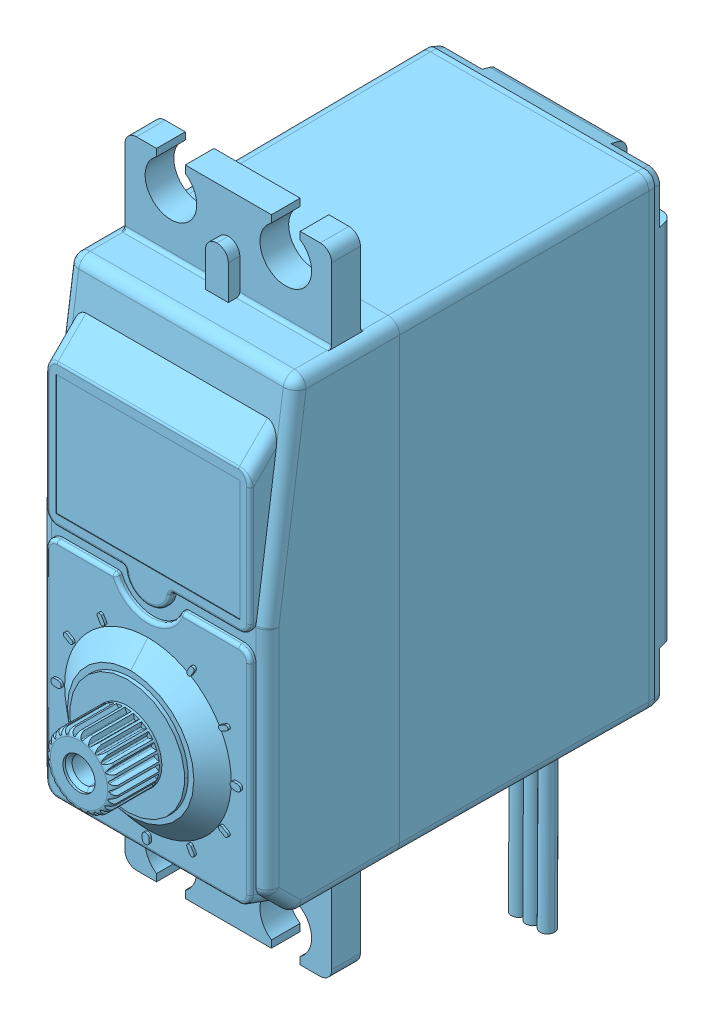
SolidWorks assembly Servo, configuration Default. Lengths in mm.
Overall size (20.01 68.31 42.11).
9 component instances, 7 part files, 0 mates.
Components (placement in the parent):
- Parallax-900-00005-08-25-Servo-CR-HSCR-STD.stp-1: Parallax-900-00005-08-25-Servo-CR-HSCR-STD.stp [Default] at origin size (21 68.31 45.51)
  - SCREW-1.7x24.stp-1: SCREW-1.7x24.stp [Default] at (0 0 -2.6) size (18 38.5 24.9)
    - b4.stp-1: b4.stp [Default] at (12.4 -16.06 -0.6) size (3 3 24.9)
    - b3.stp-1: b3.stp [Default] at (-2.6 -16.06 -0.6) size (3 3 24.9)
    - b2.stp-1: b2.stp [Default] at (-2.6 19.44 -0.6) size (3 3 24.9)
    - b1.stp-1: b1.stp [Default] at (12.4 19.44 -0.6) size (3 3 24.9)
  - HORN-D.stp-1: HORN-D.stp [Default] at (-22.975 33.5463 -1.6) x (1 0 0) z (0 -1 0) size (21 6.2 21) (hidden)
  - Screw_3x8.stp-1: Screw_3x8.stp [Default] at (62.7475 7.2555 -24.6) x (-0.749146 0.662405 0) z (0 0 1) size (5.6 5.6 10.4) (hidden)
  - Case.stp-1: Case.stp [Default] at origin size (20.01 68.31 42.11)
